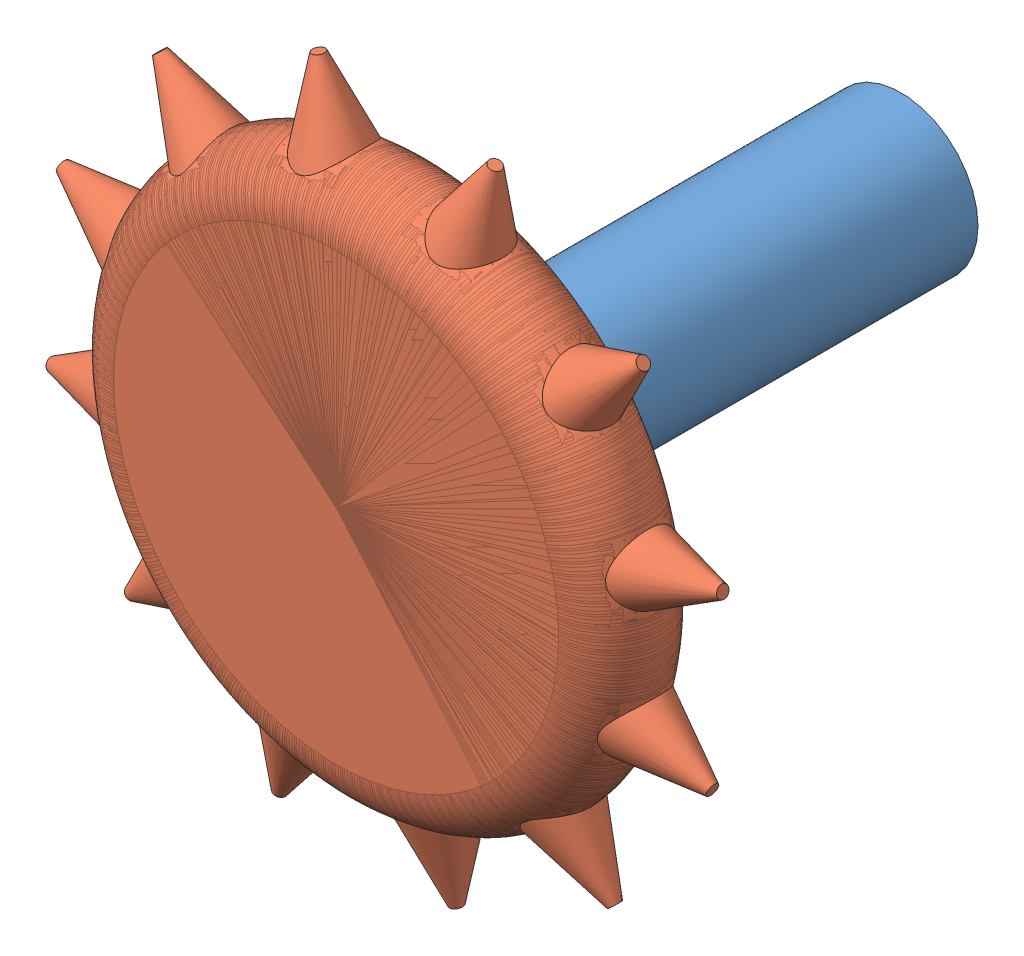
SolidWorks assembly motor_wheel_sub_assemb, configuration Default. Lengths in mm.
Overall size (313.91 313.91 165).
3 component instances, 3 part files, 5 mates.
Components (placement in the parent):
- motorV2-1: motorV2 [Default] at (39.3682 56.0325 23.8871) size (45 45 150)
- WheelV2-2: WheelV2 [Default] at (39.3682 56.0325 173.8871) x (0.747256 0.664536 0) z (0 0 1) size (230 230 30)
- key-1: key [Default] at (39.3682 59.2175 163.8871) x (0 0 -1) z (1 0 0) size (20 6 4)
Mates (geometry in assembly coordinates):
- Concentric1: concentric anti-aligned: circle of motorV2-1; circle of WheelV2-1
- Concentric2: concentric anti-aligned: circle of motorV2-1; circle of WheelV2-2
- Coincident1: coincident anti-aligned: plane of motorV2-1 through (39.3682 56.0325 173.8871) normal (0 0 1); plane of WheelV2-2 through (39.3682 56.0325 173.8871) normal (0 0 -1)
- Coincident3: coincident anti-aligned: plane of motorV2-1 through (37.3682 59.2175 153.8871) normal (0 1 0); plane of key-1 through (39.3682 59.2175 163.8871) normal (0 -1 0)
- Concentric3: concentric aligned: cylinder of motorV2-1 through (39.3682 59.2175 155.8871) axis (0 -1 0) radius 2; cylinder of key-1 through (39.3682 59.2175 155.8871) axis (0 -1 0) radius 2
